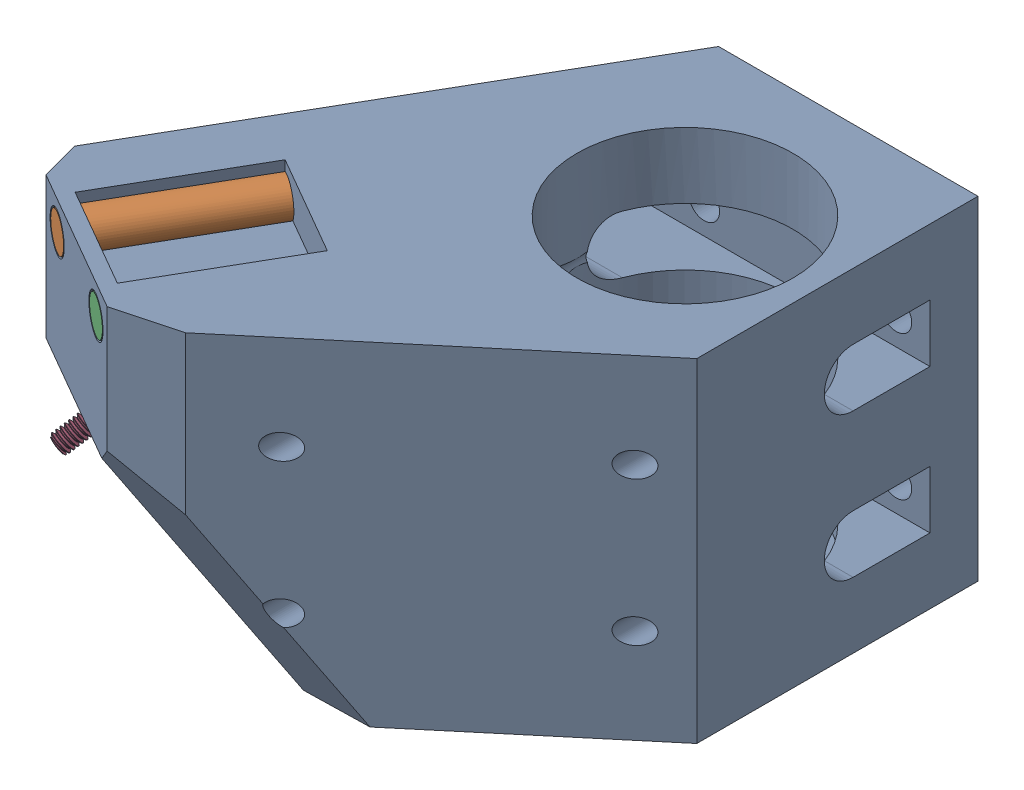
SolidWorks assembly right_coupling_side_plate_with_inserts, configuration Default. Lengths in mm.
Overall size (51.53 34.7 55.27).
4 component instances, 3 part files, 0 mates.
Components (placement in the parent):
- bed_coupling_side_plate_Front Right bed coupling lift-1: bed_coupling_side_plate_Front Right bed coupling lift [Default] at (314.9312 34.7 0) x (0 0 -1) z (1 0 0) size (55.27 34.7 51.53)
- dowel_pin_4mm_d_20mm_l_91585A457_91585A457-1: dowel_pin_4mm_d_20mm_l_91585A457_91585A457 [Default] at (285.7508 31.7 39.5099) x (0.5 0 -0.866025) z (-0.796096 0.393668 -0.459626) size (20 4 4)
- dowel_pin_4mm_d_20mm_l_91585A457_91585A457-2: dowel_pin_4mm_d_20mm_l_91585A457_91585A457 [Default] at (295.3049 31.7 45.026) x (0.5 0 -0.866025) z (0.395061 0.889889 0.228088) size (20 4 4)
- m2_set_screw_6mm_92015A093_92015A093-1: m2_set_screw_6mm_92015A093_92015A093 [Default] at (285.952 18.1526 50.1934) x (0.356323 -0.816434 -0.454389) z (-0.409576 -0.573576 0.709406) size (2.02 2.05 6.05)
